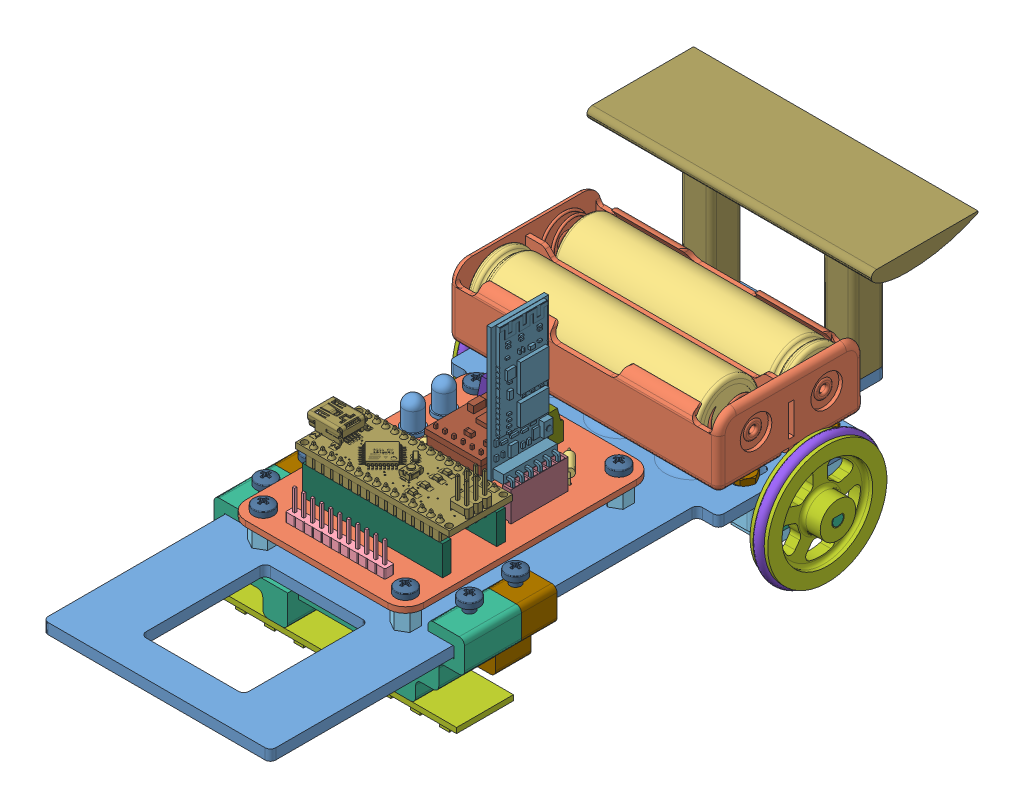
SolidWorks assembly Assembly LFR 2.0, configuration Default. Lengths in mm.
Overall size (94.86 78.51 191).
73 component instances, 30 part files, 26 mates.
Components (placement in the parent):
- Chassis-1: Chassis [Default] at (0 22.91 3.7875) x (0 0 1) z (-1 0 0) size (180.5 8 76)
- Assembly batterijhouder-1: Assembly batterijhouder [Default] at (0 30.91 3.7875) size (76 27.1 41.1)
  - Batterijhouder 2 x 18650-1: Batterijhouder 2 x 18650 [Default] x (1 0 0) z (0 1 0) size (76 41.1 19)
  - Batterij 2 x 18650-1: Batterij 2 x 18650 [Default] x (1 0 0) z (0 1 0) size (69.6 38.05 18.2)
  - countersunk flat head cross recess screw_iso-2: countersunk flat head cross recess screw_iso [ISO 7046-1 - M3 x 10 - Z - 10N] at (0 1.9 -9.925) x (0 -1 0) z (0 0 1) size (10 5.5 5.5)
  - countersunk flat head cross recess screw_iso-3: countersunk flat head cross recess screw_iso [ISO 7046-1 - M3 x 10 - Z - 10N] at (0 1.9 9.925) x (0 -1 0) z (-1 0 0) size (10 5.5 5.5)
- Assembly wiel-1: Assembly wiel [Default] at (-32.25 22.91 0) x (0 0 1) z (-1 0 0) size (35.5 35.5 35.9)
  - Motor mount-1: Motor mount [Default] at (0 0 -17.78) x (1 0 0) z (0 0 -1) size (28.57 12.7 11.43)
  - Micro Metal Gear Motor-1: Micro Metal Gear Motor [Default] at (-0.096 -5.16 -3.92) size (12 10 35.9)
  - Wiel 29.5 x 3-1: Wiel 29.5 x 3 [Default] at (-0.096 -5.16 9.68) x (-1 0 0) z (0 0 -1) size (33.5 33.5 8)
  - O-ring 29.5 x 3-1: O-ring 29.5 x 3 [Default] at (-0.096 -5.16 9.68) size (35.5 35.5 3)
  - hex thin nut chamfered gradeab_iso-1: hex thin nut chamfered gradeab_iso [ISO - 4035 - M3 - N] at (-11.2625 4.8 0) x (1 0 0) z (0 1 0) size (5.5 6.35 1.8)
  - hex thin nut chamfered gradeab_iso-2: hex thin nut chamfered gradeab_iso [ISO - 4035 - M3 - N] at (11.2625 4.8 0) x (-0.5 0 -0.866025) z (0 1 0) size (5.5 6.35 1.8)
  - pan head cross recess screw_iso-1: pan head cross recess screw_iso [ISO 7045 - M3 x 10 - Z - 10N] at (-11.2625 -7.1 0) x (0 1 0) z (-1 0 0) size (12.35 5.6 5.6)
  - pan head cross recess screw_iso-2: pan head cross recess screw_iso [ISO 7045 - M3 x 10 - Z - 10N] at (11.2625 -7.1 0) x (0 1 0) z (-1 0 0) size (12.35 5.6 5.6)
- Assembly wiel-2: Assembly wiel [Default] at (32.25 22.91 0) x (0 0 -1) z (1 0 0) size (35.5 35.5 35.9)
  - Motor mount-1: Motor mount [Default] at (0 0 -17.78) x (1 0 0) z (0 0 -1) size (28.57 12.7 11.43)
  - Micro Metal Gear Motor-1: Micro Metal Gear Motor [Default] at (-0.096 -5.16 -3.92) size (12 10 35.9)
  - Wiel 29.5 x 3-1: Wiel 29.5 x 3 [Default] at (-0.096 -5.16 9.68) x (-1 0 0) z (0 0 -1) size (33.5 33.5 8)
  - O-ring 29.5 x 3-1: O-ring 29.5 x 3 [Default] at (-0.096 -5.16 9.68) size (35.5 35.5 3)
  - hex thin nut chamfered gradeab_iso-1: hex thin nut chamfered gradeab_iso [ISO - 4035 - M3 - N] at (-11.2625 4.8 0) x (1 0 0) z (0 1 0) size (5.5 6.35 1.8)
  - hex thin nut chamfered gradeab_iso-2: hex thin nut chamfered gradeab_iso [ISO - 4035 - M3 - N] at (11.2625 4.8 0) x (-0.5 0 -0.866025) z (0 1 0) size (5.5 6.35 1.8)
  - pan head cross recess screw_iso-1: pan head cross recess screw_iso [ISO 7045 - M3 x 10 - Z - 10N] at (-11.2625 -7.1 0) x (0 1 0) z (-1 0 0) size (12.35 5.6 5.6)
  - pan head cross recess screw_iso-2: pan head cross recess screw_iso [ISO 7045 - M3 x 10 - Z - 10N] at (11.2625 -7.1 0) x (0 1 0) z (-1 0 0) size (12.35 5.6 5.6)
- Assembly PCB-1: Assembly PCB [Default] at (0 31.91 64.2875) size (50 58.6 70)
  - DRV8833-1: DRV8833 [Default] at (3 14 -9.5) x (0 0 1) z (-1 0 0) size (18.4 11.9 15.9)
  - Arduino Nano-1: Arduino Nano [Default] at (0.3598 23.6638 20.3801) x (-1 0 0) z (0 0 -1) size (44.95 20.74 17.81)
  - Header6P-1: Header6P [Default] at (9.35 1.6 -17.1) x (-1 0 0) z (0 1 0) size (16.1 2.4 11.5)
  - Header6P-2: Header6P [Default] at (9.35 1.6 -1.9) x (-1 0 0) z (0 1 0) size (16.1 2.4 11.5)
  - HC-05-2: HC-05 [Varsayılan] at (11.45 46.6 -1.45) x (0 -1 0) z (1 0 0) size (42.6 16.1 5.9)
  - Header6P-3: Header6P [Default] at (17 1.6 -3.15) x (0 0 -1) z (0 1 0) size (16.1 2.4 11.5)
  - Header15P-1: Header15P [Default] at (-15.76 2.4 4.86) x (-1 0 0) z (0 1 0) size (39.38 2.4 11.5)
  - Header15P-2: Header15P [Default] at (-15.76 2.4 20.0812) x (-1 0 0) z (0 1 0) size (39.38 2.4 11.5)
  - ScrewTerminal x 4-1: ScrewTerminal x 4 [Default] at (0 1.6 -26) x (-1 0 0) z (0 0 -1) size (10.62 12 6.3)
  - ScrewTerminal x 2-1: ScrewTerminal x 2 [Default] at (-10.48 1.6 -26) x (-1 0 0) z (0 0 -1) size (5.54 12 6.3)
  - Push button-1: Push button [Default] at (-18.25 1.6 -2.35) x (0 0 1) z (-1 0 0) size (7.14 7.7 6)
  - Led-1: Led [Default] at (-18.5 1.6 -19.33) x (0 0 1) z (-1 0 0) size (5.8 11.9 5.8)
  - PCB 50 x 70-3: PCB 50 x 70 [Default] at origin size (50 1.6 70)
  - Led-2: Led [Default] at (-18.5 1.6 -10.59) x (0 0 1) z (-1 0 0) size (5.8 11.9 5.8)
  - Weerstand-1: Weerstand [Default] at (-10.4645 1.6 -14.4645) x (0.707107 0 -0.707107) z (0.707107 0 0.707107) size (2.5 5.7 10.5)
  - Weerstand-2: Weerstand [Default] at (-10.4645 1.6 -5.9645) x (0.707107 0 -0.707107) z (0.707107 0 0.707107) size (2.5 5.7 10.5)
  - Weerstand-3: Weerstand [Default] at (13.0355 1.6 -22.9645) x (0.707107 0 -0.707107) z (0.707107 0 0.707107) size (2.5 5.7 10.5)
  - Header11P-1: Header11P [Default] at (0 1.6 28.5) size (27.94 11.74 2.54)
  - M3 spacer 6 mm-1: M3 spacer 6 mm [Default] at (20 -6 -30) size (5.6 12 6.47)
  - M3 spacer 6 mm-2: M3 spacer 6 mm [Default] at (-20 -6 -30) x (0.5 0 0.866025) z (-0.866025 0 0.5) size (5.6 12 6.47)
  - M3 spacer 6 mm-3: M3 spacer 6 mm [Default] at (-20 -6 30) x (0.5 0 0.866025) z (-0.866025 0 0.5) size (5.6 12 6.47)
  - M3 spacer 6 mm-4: M3 spacer 6 mm [Default] at (20 -6 30) size (5.6 12 6.47)
  - pan head cross recess screw_iso-1: pan head cross recess screw_iso [ISO 7045 - M3 x 5 - Z - 5N] at (20 4 30) x (0 -1 0) z (0 0 1) size (7.35 5.6 5.6)
  - pan head cross recess screw_iso-2: pan head cross recess screw_iso [ISO 7045 - M3 x 5 - Z - 5N] at (20 4 -30) x (0 -1 0) z (0 0 1) size (7.35 5.6 5.6)
  - pan head cross recess screw_iso-3: pan head cross recess screw_iso [ISO 7045 - M3 x 5 - Z - 5N] at (-20 4 30) x (0 -1 0) z (0 0 1) size (7.35 5.6 5.6)
  - pan head cross recess screw_iso-4: pan head cross recess screw_iso [ISO 7045 - M3 x 5 - Z - 5N] at (-20 4 -30) x (0 -1 0) z (0 0 1) size (7.35 5.6 5.6)
  - hex thin nut chamfered gradeab_iso-1: hex thin nut chamfered gradeab_iso [ISO - 4035 - M3 - N] at (20 -10.8 -30) x (1 0 0) z (0 -1 0) size (5.5 6.35 1.8)
  - hex thin nut chamfered gradeab_iso-2: hex thin nut chamfered gradeab_iso [ISO - 4035 - M3 - N] at (20 -10.8 30) x (1 0 0) z (0 -1 0) size (5.5 6.35 1.8)
  - hex thin nut chamfered gradeab_iso-3: hex thin nut chamfered gradeab_iso [ISO - 4035 - M3 - N] at (-20 -10.8 30) x (0.5 0 -0.866025) z (0 -1 0) size (5.5 6.35 1.8)
  - hex thin nut chamfered gradeab_iso-4: hex thin nut chamfered gradeab_iso [ISO - 4035 - M3 - N] at (-20 -10.8 -30) x (1 0 0) z (0 -1 0) size (5.5 6.35 1.8)
- Assembly schuiver QTR-8A-1: Assembly schuiver QTR-8A [Default] at (0 25.91 90.3699) size (70.5 30.71 16)
  - QTR-8A schuiver-1: QTR-8A schuiver [Default] at (0 0 -13.425) size (70.5 22.5 16)
  - QTR-8A-1: QTR-8A [Default] at (0 -21 -5.425) x (1 0 0) z (0 0 -1) size (66 3.1 16)
  - Header11P90-1: Header11P90 [Default] at (-12.7 -22.46 -12.155) x (0 0 1) z (0 1 0) size (8.45 27.94 7.3)
  - pan head cross recess screw_iso-1: pan head cross recess screw_iso [ISO 7045 - M3 x 10 - Z - 10N] at (18 -23.4 -9.925) x (0 1 0) z (1 0 0) size (12.35 5.6 5.6)
  - pan head cross recess screw_iso-2: pan head cross recess screw_iso [ISO 7045 - M3 x 10 - Z - 10N] at (-18 -23.4 -9.925) x (0 1 0) z (1 0 0) size (12.35 5.6 5.6)
  - pan head cross recess screw_iso-3: pan head cross recess screw_iso [ISO 7045 - M3 x 5 - Z - 5N] at (-28.625 7.4 -5.425) x (0 -1 0) z (0 0 1) size (7.35 5.6 5.6)
  - pan head cross recess screw_iso-4: pan head cross recess screw_iso [ISO 7045 - M3 x 5 - Z - 5N] at (28.625 7.4 -5.425) x (0 -1 0) z (0 0 1) size (7.35 5.6 5.6)
- Assembly schuiver M3 ronde kop-1: Assembly schuiver M3 ronde kop [Default] at (0 25.91 71.9449) size (70.5 33.1 10)
  - M3 ronde kop schuiver-1: M3 ronde kop schuiver [Default] at (0 0 -5) size (70.5 20.75 10)
  - M3 ronde kop-1: M3 ronde kop [Default] at (0 -17.75 0) size (5.77 15 5)
  - pan head cross recess screw_iso-1: pan head cross recess screw_iso [ISO 7045 - M3 x 5 - Z - 5N] at (28.625 7.4 0) x (0 -1 0) z (0 0 1) size (7.35 5.6 5.6)
  - pan head cross recess screw_iso-2: pan head cross recess screw_iso [ISO 7045 - M3 x 5 - Z - 5N] at (-28.625 7.4 0) x (0 -1 0) z (0 0 1) size (7.35 5.6 5.6)
- KCD11-1: KCD11 [KCD11-A-101-O11XX] at (0 17.21 -26.4625) size (15.06 19.01 10.5)
- Assembly spoiler-1: Assembly spoiler [Default] at (0 25.91 -31.7125) size (80 45.35 30)
  - Spoiler-1: Spoiler [Default] at (0 40 0) x (1 0 0) z (0 0 -1) size (80 40 30)
  - pan head cross recess screw_iso-1: pan head cross recess screw_iso [ISO 7045 - M3 x 10 - Z - 10N] at (20 -5.4 0) x (0 1 0) z (-1 0 0) size (12.35 5.6 5.6)
  - pan head cross recess screw_iso-2: pan head cross recess screw_iso [ISO 7045 - M3 x 10 - Z - 10N] at (-20 -5.4 0) x (0 1 0) z (-1 0 0) size (12.35 5.6 5.6)
Mates (geometry in assembly coordinates):
- Coincident36: coincident anti-aligned: plane of Chassis-1 through (0 22.91 3.7875) normal (-1 0 0)
- Coincident54: coincident anti-aligned: plane of Chassis-1 through (0 25.91 3.7875) normal (0 1 0); plane of KCD11-1 through (-7.5 25.91 -21.2125) normal (0 -1 0)
- Coincident55: coincident: point of Chassis-1; plane of KCD11-1 through (0 17.21 -26.4625) normal (0 0 1)
- Coincident56: coincident aligned: plane of assembly through (0 0 0) normal (1 0 0); plane of KCD11-1 through (0 17.21 -26.4625) normal (1 0 0)
- Coincident103: coincident anti-aligned: plane of Chassis-1 through (0 22.91 3.7875) normal (0 -1 0); plane of Assembly wiel-1/Motor mount-1 through (-37.33 22.91 -14.2875) normal (0 1 0)
- Slot1: slot aligned: cylinder of Chassis-1; cylinder of Assembly wiel-1/Motor mount-1 through (-32.25 24.18 -11.2625) axis (0 -1 0) radius 1.5875; cylinder of Chassis-1 through (-32.25 30.91 -11.2625) axis (0 -1 0) radius 1.5
- Coincident105: coincident anti-aligned: plane of Chassis-1 through (0 22.91 3.7875) normal (0 -1 0); plane of Assembly wiel-2/Motor mount-1 through (37.33 22.91 -14.2875) normal (0 1 0)
- Slot2: slot aligned: cylinder of Assembly wiel-2/Motor mount-1 through (32.25 24.18 -11.2625) axis (0 -1 0) radius 1.5875; plane of Chassis-1 through (30.75 30.91 -5.2625) normal (1 0 0); cylinder of Chassis-1 through (32.25 30.91 -5.2625) axis (0 -1 0) radius 1.5
- Coincident107: coincident aligned: plane of Assembly wiel-1/O-ring 29.5 x 3-1 through (-41.93 0 -0.096) normal (0 1 0)
- Concentric544: concentric anti-aligned: cylinder of Chassis-1 through (-20 30.91 34.2875) axis (0 -1 0) radius 1.25; cylinder of Assembly PCB-1/M3 spacer 6 mm-2 through (-20 19.91 34.2875) axis (0 1 0) radius 1.5
- Concentric545: concentric anti-aligned: cylinder of Chassis-1 through (20 30.91 94.2875) axis (0 -1 0) radius 1.25; cylinder of Assembly PCB-1/M3 spacer 6 mm-4 through (20 19.91 94.2875) axis (0 1 0) radius 1.5
- Coincident108: coincident anti-aligned: plane of Chassis-1 through (0 25.91 3.7875) normal (0 1 0); plane of Assembly PCB-1/M3 spacer 6 mm-3 through (-20 25.91 94.2875) normal (0 -1 0)
- Coincident109: coincident anti-aligned: plane of Chassis-1 through (0 25.91 3.7875) normal (0 1 0); plane of Assembly schuiver QTR-8A-1/QTR-8A schuiver-1 through (-25 25.91 92.9449) normal (0 -1 0)
- Coincident110: coincident aligned: plane of Assembly schuiver QTR-8A-1 through (0 25.91 90.3699) normal (1 0 0)
- Coincident111: coincident aligned: plane of Chassis-1 through (0 25.91 3.7875) normal (0 1 0); plane of Assembly schuiver M3 ronde kop-1 through (0 25.91 71.9449) normal (0 1 0)
- Coincident112: coincident aligned: plane of Assembly schuiver M3 ronde kop-1 through (0 25.91 71.9449) normal (1 0 0)
- Concentric546: concentric anti-aligned: cylinder of Chassis-1 through (0 30.91 -6.1375) axis (0 -1 0) radius 1.25; cylinder of Assembly batterijhouder-1/Batterijhouder 2 x 18650-1 through (0 -55.6426 -6.1375) axis (0 1 0) radius 1.55
- Concentric547: concentric anti-aligned: cylinder of Chassis-1 through (0 30.91 13.7125) axis (0 -1 0) radius 1.25; cylinder of Assembly batterijhouder-1/Batterijhouder 2 x 18650-1 through (0 -55.6426 13.7125) axis (0 1 0) radius 1.55
- Coincident113: coincident anti-aligned: plane of Chassis-1 through (-20 30.91 13.7125) normal (0 1 0); plane of Assembly batterijhouder-1/Batterijhouder 2 x 18650-1 through (0 30.91 3.7875) normal (0 -1 0)
- Coincident114: coincident aligned: plane of Assembly wiel-1 through (-32.25 22.91 0) normal (0 0 1)
- Concentric548: concentric aligned: cylinder of Chassis-1 through (-20 25.91 -31.7125) axis (0 -1 0) radius 1.25; cylinder of Assembly spoiler-1/Spoiler-1 through (-20 35.91 -31.7125) axis (0 -1 0) radius 1.25
- Concentric549: concentric aligned: cylinder of Chassis-1 through (20 25.91 -31.7125) axis (0 -1 0) radius 1.25; cylinder of Assembly spoiler-1/Spoiler-1 through (20 35.91 -31.7125) axis (0 -1 0) radius 1.25
- Coincident115: coincident anti-aligned: plane of Chassis-1 through (0 25.91 3.7875) normal (0 1 0); plane of Assembly spoiler-1/Spoiler-1 through (0 25.91 -31.7125) normal (0 -1 0)
- LimitDistance6: limit distance = 41.1574 mm: plane of Assembly schuiver M3 ronde kop-1/M3 ronde kop schuiver-1 through (0 25.91 66.9449) normal (0 0 -1); line of Chassis-1 through (-32 25.91 25.7875) axis (0 -1 0)
- LimitDistance7: limit distance = 0 mm anti-aligned: plane of Assembly schuiver QTR-8A-1/QTR-8A schuiver-1 through (0 25.91 76.9449) normal (0 0 -1); plane of Assembly schuiver M3 ronde kop-1/M3 ronde kop schuiver-1 through (0 25.91 76.9449) normal (0 0 1)
- Slot5: slot aligned: plane of Chassis-1 through (30.75 30.91 3.7875) normal (1 0 0); cylinder of Assembly wiel-2/Motor mount-1 through (32.25 24.18 11.2625) axis (0 -1 0) radius 1.5875; cylinder of Chassis-1 through (32.25 30.91 12.8375) axis (0 -1 0) radius 1.5
